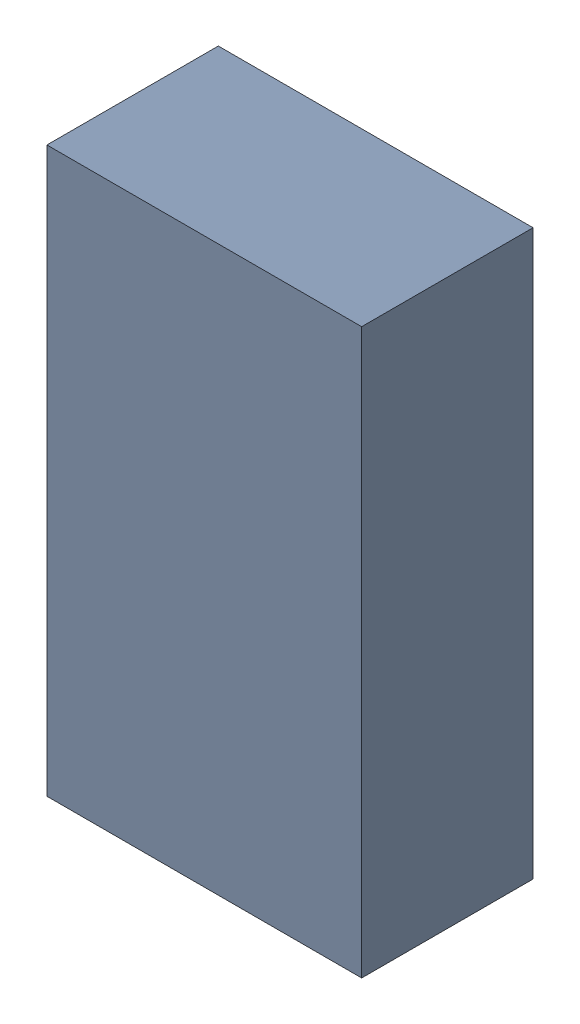
SolidWorks assembly R18, configuration Default. Lengths in mm.
Overall size (1.01 1.81 0.56).
3 component instances, 2 part files, 0 mates.
Components (placement in the parent):
- 1088887696-1: 1088887696 [Default] at (3.15 45.05 -2.194) size (1.01 1.81 0.55)
  - Extruded-29-1: Extruded-29 [Default] at origin size (1.01 1.81 0.55)
- R0603-1: R0603 [Default] at (3.1499 45.0499 -1.644) x (0 -1 0) z (1 0 0) size (1.7 0.56 0.8)
